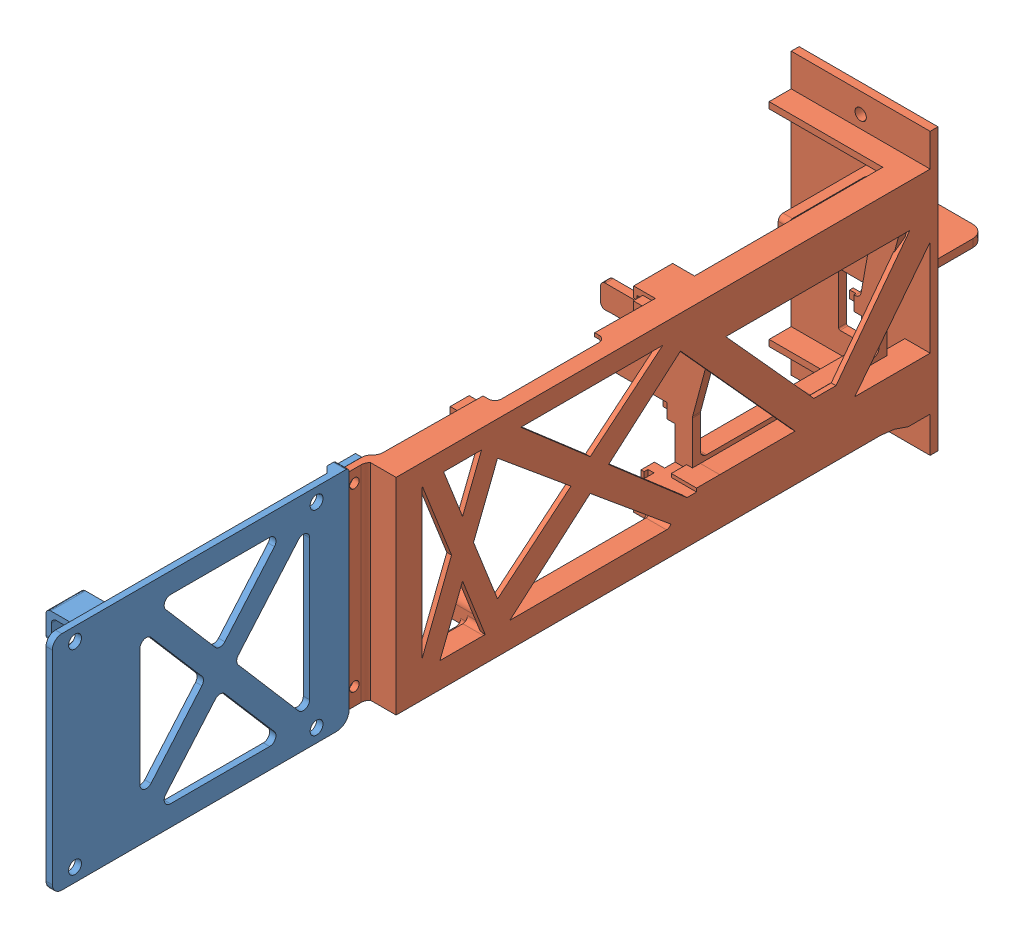
SolidWorks assembly sbc_rack_dhem_v2, configuration Default. Lengths in mm.
Overall size (122.38 127.76 316.25).
2 component instances, 2 part files, 2 mates.
Components (placement in the parent):
- Rack_basecopy_hd-1: Rack_basecopy_hd [Default] at (8.6866 124.3229 84.6246) size (25.6 70.35 273.5)
- Rack_basecopy_2-1: Rack_basecopy_2 [Default] at (10.6866 124.3236 78.6246) size (122.38 127.76 316.25)
Mates (geometry in assembly coordinates):
- Coincident10: coincident aligned: line of Rack_basecopy_hd-1 through (21.6866 158.4979 256.1246) axis (0 -1 0); line of Rack_basecopy_2-1 through (21.6866 159.4986 256.1246) axis (0 -1 0)
- Coincident13: coincident aligned: plane of Rack_basecopy_hd-1 through (17.6866 93.2236 84.6246) normal (0 -1 0); plane of Rack_basecopy_2-1 through (10.6866 93.2236 78.6246) normal (0 -1 0)
